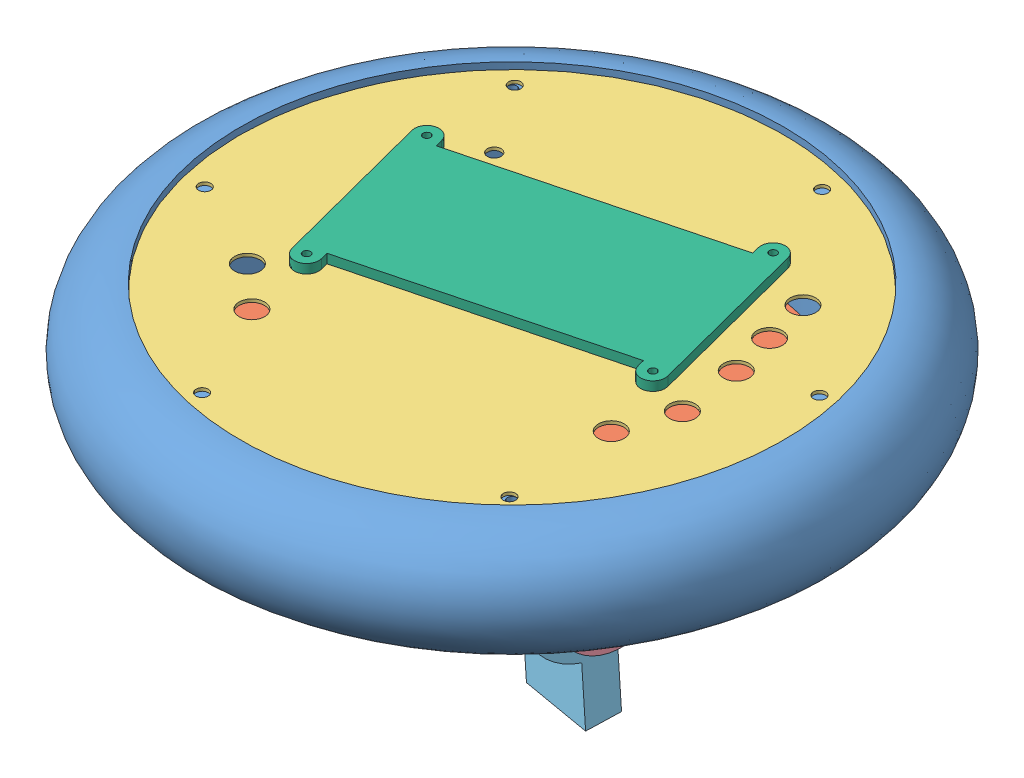
SolidWorks assembly Steering Wheel V3, configuration Default. Lengths in mm.
Overall size (216.83 136.16 216.83).
6 component instances, 6 part files, 14 mates.
Components (placement in the parent):
- Ring-1: Ring [Default] at (45.2044 134.2508 203.2364) size (215.9 38.1 215.9)
- BackPlate-1: BackPlate [Default] at (45.2044 115.2008 203.2364) x (0 0 -1) z (0 1 0) size (177.8 177.8 62.41)
- FrontPlate-1: FrontPlate [Default] at (45.2044 150.1258 203.2364) x (0.967803 0 -0.251708) z (0 1 0) size (177.8 177.8 1.02)
- AnalogueBrakeMountingRod-1: AnalogueBrakeMountingRod [Default] at (77.3597 86.6258 207.4645) x (0.171388 0 -0.985204) z (-0.985204 0 -0.171388) size (31.75 44.45 55.25)
- MockAnalogueBrake-1: MockAnalogueBrake [Default] at (77.3597 86.6258 207.4645) x (0.124728 -0.685837 -0.716987) z (-0.985204 0 -0.171388) size (53.4 57.6 23.81)
- Acrylic Screen Cover-1: Acrylic Screen Cover [Default] at (42.0077 154.1418 190.9453) x (0.967803 0 -0.251708) z (0 -1 0) size (101 63 3)
Mates (geometry in assembly coordinates):
- Coincident1: coincident anti-aligned: plane of Ring-1 through (-30.9956 150.1258 203.2364) normal (0 1 0); plane of FrontPlate-1 through (45.2044 150.1258 203.2364) normal (0 -1 0)
- Coincident2: coincident anti-aligned: plane of Ring-1 through (-43.6956 118.3758 203.2364) normal (0 -1 0); plane of BackPlate-1 through (45.2044 118.3758 203.2364) normal (0 1 0)
- Concentric5: concentric aligned: cylinder of Ring-1 through (45.2044 134.2508 203.2364) axis (0 -1 0) radius 88.9; cylinder of FrontPlate-1 through (45.2044 151.1418 203.2364) axis (0 -1 0) radius 88.9
- Concentric6: concentric aligned: cylinder of Ring-1 through (45.2044 134.2508 203.2364) axis (0 -1 0) radius 88.9; cylinder of BackPlate-1 through (45.2044 118.3758 203.2364) axis (0 -1 0) radius 88.9
- Concentric9: concentric: cylinder of Ring-1 through (-31.0618 134.2508 234.8269) axis (0 1 0) radius 3.175; cylinder of FrontPlate-1 through (-31.0618 151.7133 234.8269) axis (0 -1 0) radius 2.3813
- Concentric10: concentric aligned: cylinder of Ring-1 through (-37.3456 275.8558 203.2364) axis (0 -1 0) radius 1.5875; cylinder of BackPlate-1 through (-37.3456 118.3758 203.2364) axis (0 -1 0) radius 2.3813
- Coincident5: coincident anti-aligned: plane of BackPlate-1 through (45.2044 115.2008 203.2364) normal (0 -1 0); plane of AnalogueBrakeMountingRod-1 through (86.3365 115.2008 192.9127) normal (0 1 0)
- Concentric11: concentric aligned: cylinder of AnalogueBrakeMountingRod-1 through (54.2123 86.6258 203.4378) axis (0.985204 0 0.171388) radius 11.1125; cylinder of MockAnalogueBrake-1 through (53.8995 86.6258 203.3834) axis (0.985204 0 0.171388) radius 11.1125
- Coincident6: coincident anti-aligned: plane of AnalogueBrakeMountingRod-1 through (77.3597 86.6258 207.4645) normal (-0.985204 0 -0.171388); plane of MockAnalogueBrake-1 through (77.3597 86.6258 207.4645) normal (0.985204 0 0.171388)
- Coincident7: coincident anti-aligned: plane of Ring-1 through (-30.9956 118.3758 203.2364) normal (0 -1 0); plane of BackPlate-1 through (45.2044 118.3758 203.2364) normal (0 1 0)
- Coincident9: coincident anti-aligned: plane of Ring-1 through (-30.9956 150.1258 203.2364) normal (0 1 0); plane of FrontPlate-1 through (45.2044 150.1258 203.2364) normal (0 -1 0)
- Concentric13: concentric aligned: cylinder of FrontPlate-1 through (80.0886 147.9668 152.6263) axis (0 1 0) radius 1.25; cylinder of Acrylic Screen Cover-1 through (80.0886 151.1418 152.6263) axis (0 1 0) radius 1.25
- Concentric14: concentric aligned: cylinder of FrontPlate-1 through (3.9268 147.9668 229.2643) axis (0 1 0) radius 1.25; cylinder of Acrylic Screen Cover-1 through (3.9268 151.1418 229.2643) axis (0 1 0) radius 1.25
- Coincident10: coincident anti-aligned: plane of FrontPlate-1 through (45.2044 151.1418 203.2364) normal (0 1 0); plane of Acrylic Screen Cover-1 through (80.0886 151.1418 152.6263) normal (0 -1 0)
